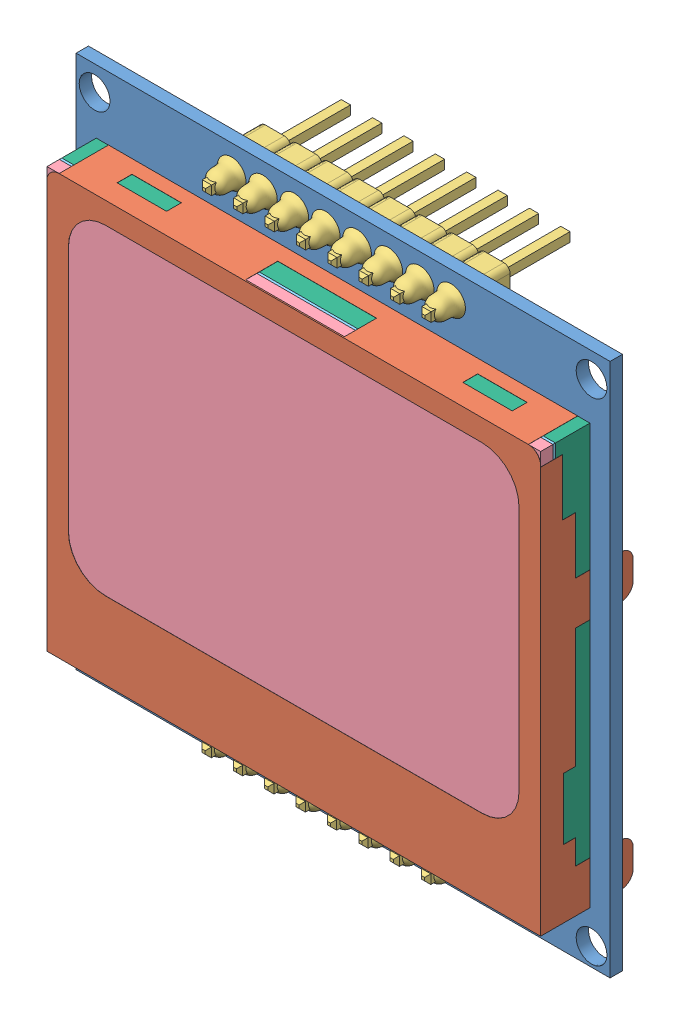
SolidWorks assembly Nokia5110LCD, configuration Valor predeterminado. Lengths in mm.
Overall size (43.25 43.25 13.5).
7 component instances, 6 part files, 15 mates.
Components (placement in the parent):
- placa-1: placa [Valor predeterminado] at (-21.1383 -20.2257 43.25) size (43.25 43.25 1)
- display-1: display [Valor predeterminado] at (-19.5133 -16.1095 48.24) size (40 34 7.5)
- 8pin_header-1: 8pin_header [Default] at (9.2419 20.8813 43.25) x (0 1 0) z (-1 0 0) size (2.64 11.75 20.42)
- 8pin_header-2: 8pin_header [Default] at (9.2149 -18.5582 43.25) x (0 1 0) z (-1 0 0) size (2.64 11.75 20.42)
- vidro-1: vidro [Valor predeterminado] at (-19.5033 -16.0995 47.24) size (39.98 33.98 1)
- cristal_liquido-1: cristal_liquido [Valor predeterminado] at (-19.5033 -16.0995 47.04) size (39.98 33.98 0.2)
- cristal_inferior-1: cristal_inferior [Valor predeterminado] at (-19.5033 -16.0995 44.25) size (39.98 33.98 2.79)
Mates (geometry in assembly coordinates):
- Coincidente2: coincident: plane of placa-1 through (-21.1383 -20.2257 43.25) normal (0 0 -1); plane of 8pin_header-1 through (8.4719 21.6513 43.25) normal (0 0 1)
- Paralelo1: parallel: plane of placa-1 through (-21.1383 23.0243 44.25) normal (0 1 0); plane of 8pin_header-1 through (-9.3081 19.6113 40.75) normal (0 -1 0)
- Coincidente4: coincident: plane of placa-1 through (-21.1383 -20.2257 43.25) normal (0 0 -1); plane of 8pin_header-2 through (8.4449 -17.7882 43.25) normal (0 0 1)
- Paralelo2: parallel: plane of placa-1 through (-21.1383 23.0243 44.25) normal (0 1 0); plane of 8pin_header-2 through (-9.3351 -19.8282 40.75) normal (0 -1 0)
- Coincidente7: coincident: plane of placa-1 through (-21.1383 -20.2257 44.25) normal (0 0 1); plane of display-1 through (-7.7802 -16.0995 44.25) normal (0 0 -1)
- Coincidente8: coincident: plane of display-1 through (-18.7802 16.8905 48.24) normal (0 0 -1); plane of vidro-1 through (-19.7702 -16.0995 48.24) normal (0 0 1)
- Coincidente11: coincident: plane of display-1 through (-19.7702 6.5905 41.75) normal (1 0 0); plane of vidro-1 through (-19.7702 -16.0995 48.24) normal (-1 0 0)
- Coincidente12: coincident: plane of display-1 through (-19.7802 -16.0995 48.24) normal (0 1 0); plane of vidro-1 through (-19.7702 -16.0995 48.24) normal (0 -1 0)
- Coincidente13: coincident: plane of vidro-1 through (-19.7702 -16.0995 47.24) normal (0 0 -1); plane of cristal_liquido-1 through (-19.7702 -16.0995 47.24) normal (0 0 1)
- Coincidente14: coincident: plane of display-1 through (-19.7802 -16.0995 48.24) normal (0 1 0); plane of cristal_liquido-1 through (-19.7702 -16.0995 47.24) normal (0 -1 0)
- Coincidente15: coincident: plane of display-1 through (-19.7702 6.5905 41.75) normal (1 0 0); plane of cristal_liquido-1 through (-19.7702 -16.0995 47.24) normal (-1 0 0)
- Coincidente16: coincident: plane of display-1 through (-19.7802 -16.0995 48.24) normal (0 1 0); plane of cristal_inferior-1 through (-19.7702 -16.0995 47.04) normal (0 -1 0)
- Coincidente17: coincident: plane of display-1 through (-19.7702 6.5905 41.75) normal (1 0 0); plane of cristal_inferior-1 through (-19.7702 -16.0995 47.04) normal (-1 0 0)
- Coincidente18: coincident: plane of cristal_liquido-1 through (-19.7702 -16.0995 47.04) normal (0 0 -1); plane of cristal_inferior-1 through (-19.7702 -16.0995 47.04) normal (0 0 1)
- Distance1: distance = 1.625 mm: plane of display-1 through (-19.5133 6.5905 41.75) normal (-1 0 0); plane of placa-1 through (-21.1383 -20.2257 44.25) normal (-1 0 0)
